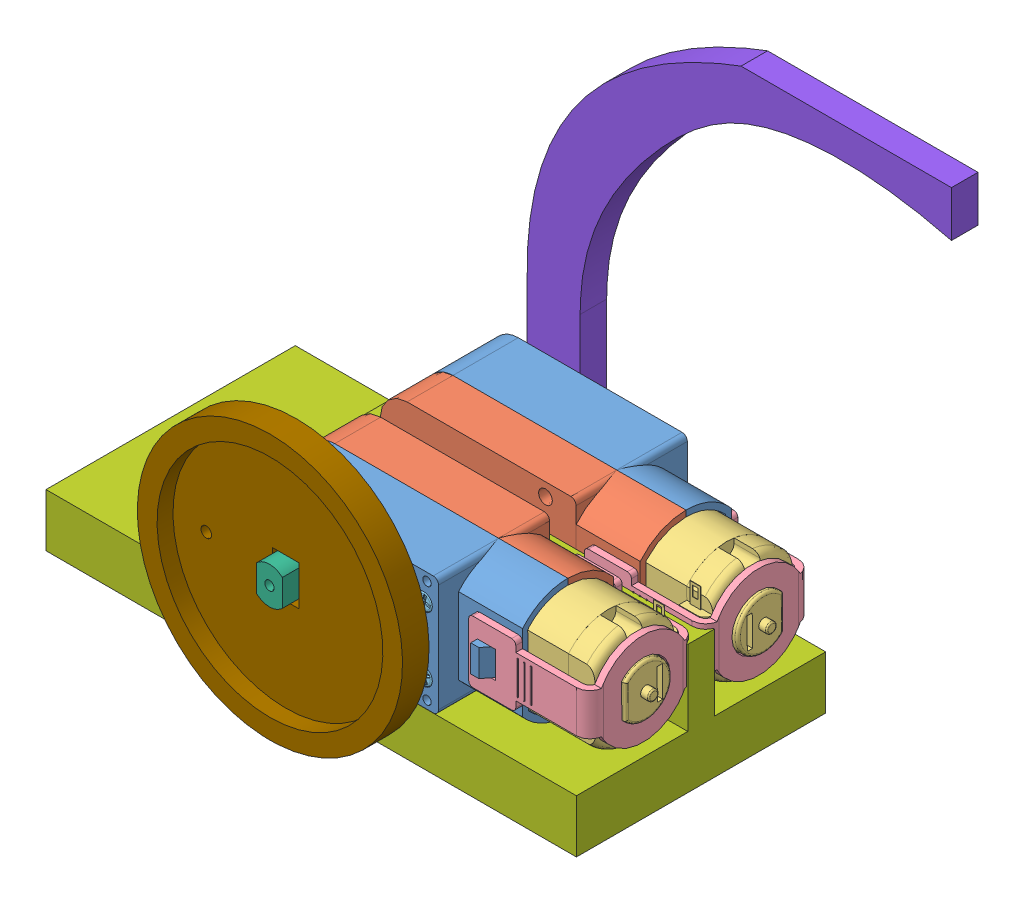
SolidWorks assembly Robot, configuration Défaut. Lengths in mm.
Overall size (122.92 100.89 58.58).
19 component instances, 9 part files, 13 mates.
Components (placement in the parent):
- Solarbotics_GM9-Assem-1: Solarbotics_GM9-Assem [Default] at (40.229 34.2745 -32.8195) x (-1 0 0) z (0 0 1) size (70.24 22.35 29.33)
  - GM9-driver_side-1: GM9-driver_side [Default] at origin size (54.05 22.35 14.22)
  - GM9-encoder_side-1: GM9-encoder_side [Default] x (1 0 0) z (0 0 -1) size (54.05 22.35 11.17)
  - RM3-regular motor-1: RM3-regular motor [Default] at (-45.785 -0.0593 0.0007) x (0 0.999923 -0.012377) z (-1 0 0) size (19.88 16.59 37.51)
  - GMstrap2-1: GMstrap2 [Default] at (-52.055 -3.937 -10.2616) x (0 0 1) z (1 0 0) size (20.32 17.53 22.86)
  - screw_head1-1: screw_head1 [Default] at (-23.2283 6.0833 10.795) x (0.902065 0.4316 0) z (0 0 1) size (3.5 3.5 1.53)
  - screw_head1-2: screw_head1 [Default] at (-23.2283 -6.0833 10.795) x (0.970455 -0.241284 0) z (0 0 1) size (3.5 3.5 1.53)
  - output shaft-1: output shaft [Default] at (0 0 12.319) size (6.99 6.99 5.83)
- Base-1: Base [Défaut] at (42.307 13.0985 -43.9555) size (100 24.22 47)
- Solarbotics_GM9-Assem-2: Solarbotics_GM9-Assem [Default] at (40.229 34.2745 -55.0915) x (-1 0 0) z (0 0 -1) size (70.24 22.35 29.33)
  - GM9-driver_side-1: GM9-driver_side [Default] at origin size (54.05 22.35 14.22)
  - GM9-encoder_side-1: GM9-encoder_side [Default] x (1 0 0) z (0 0 -1) size (54.05 22.35 11.17)
  - RM3-regular motor-1: RM3-regular motor [Default] at (-45.785 -0.0593 0.0007) x (0 0.999923 -0.012377) z (-1 0 0) size (19.88 16.59 37.51)
  - GMstrap2-1: GMstrap2 [Default] at (-52.055 -3.937 -10.2616) x (0 0 1) z (1 0 0) size (20.32 17.53 22.86)
  - screw_head1-1: screw_head1 [Default] at (-23.2283 6.0833 10.795) x (0.902065 0.4316 0) z (0 0 1) size (3.5 3.5 1.53)
  - screw_head1-2: screw_head1 [Default] at (-23.2283 -6.0833 10.795) x (0.970455 -0.241284 0) z (0 0 1) size (3.5 3.5 1.53)
  - output shaft-1: output shaft [Default] at (0 0 12.319) size (6.99 6.99 5.83)
- Patte-2: Patte [Défaut] at (40.229 34.2618 -73.2445) size (80.54 95.7 5)
- Roue-1: Roue [Défaut] at (40.316 34.067 -19.6665) x (0 -1 0) z (0 0 1) size (50 50 5)
Mates (geometry in assembly coordinates):
- Coïncidente10: coincident: plane of Solarbotics_GM9-Assem-1/GM9-encoder_side-1 through (29.307 23.0985 -41.4555) normal (0 -1 0); plane of Base-1 through (42.307 23.0985 -43.9555) normal (0 1 0)
- Coïncidente11: coincident: plane of Solarbotics_GM9-Assem-1/GM9-encoder_side-1 through (29.307 45.4505 -41.4555) normal (0 0 -1); plane of Base-1 through (92.307 37.3185 -41.4555) normal (0 0 1)
- Coïncidente12: coincident: plane of Solarbotics_GM9-Assem-1/GM9-encoder_side-1 through (29.307 45.4505 -41.4555) normal (-1 0 0); plane of Base-1 through (29.307 37.3185 -43.9555) normal (1 0 0)
- Coïncidente16: coincident: plane of Base-1 through (92.307 37.3185 -46.4555) normal (0 0 -1); plane of Solarbotics_GM9-Assem-2/GM9-encoder_side-1 through (29.307 23.0985 -46.4555) normal (0 0 1)
- Coïncidente17: coincident: plane of Base-1 through (29.307 37.3185 -43.9555) normal (1 0 0); plane of Solarbotics_GM9-Assem-2/GM9-driver_side-1 through (29.307 45.4505 -67.4105) normal (-1 0 0)
- Coïncidente18: coincident: plane of Base-1 through (92.307 37.3185 -46.4555) normal (0 0 -1); plane of Solarbotics_GM9-Assem-2/GM9-encoder_side-1 through (29.307 23.0985 -46.4555) normal (0 0 1)
- Coïncidente19: coincident: plane of Base-1 through (42.307 23.0985 -43.9555) normal (0 1 0); plane of Solarbotics_GM9-Assem-2/GM9-driver_side-1 through (29.307 23.0985 -67.4105) normal (0 -1 0)
- Coïncidente20: coincident: plane of Solarbotics_GM9-Assem-2/output shaft-1 through (42.642 31.7496 -73.2445) normal (1 0 0); plane of Patte-2 through (42.642 34.2618 -68.2445) normal (-1 0 0)
- Coïncidente21: coincident: moEndPointRef_w of Solarbotics_GM9-Assem-2/output shaft-1; plane of Patte-2 through (40.229 37.767 -68.2445) normal (0 -1 0)
- Coïncidente22: coincident: plane of Solarbotics_GM9-Assem-2/output shaft-1 through (40.229 34.2745 -73.2445) normal (0 0 -1); plane of Patte-2 through (40.229 34.2618 -73.2445) normal (0 0 -1)
- Coïncidente23: coincident: plane of Solarbotics_GM9-Assem-1/output shaft-1 through (37.816 36.7993 -14.6665) normal (-1 0 0); plane of Roue-1 through (37.816 37.767 -14.6665) normal (1 0 0)
- Coïncidente24: coincident: moEndPointRef_w of Solarbotics_GM9-Assem-1/output shaft-1; plane of Roue-1 through (42.816 37.767 -14.6665) normal (0 -1 0)
- Coïncidente25: coincident: plane of Solarbotics_GM9-Assem-1/output shaft-1 through (40.229 34.2745 -14.6665) normal (0 0 1); plane of Roue-1 through (40.316 34.067 -14.6665) normal (0 0 1)
